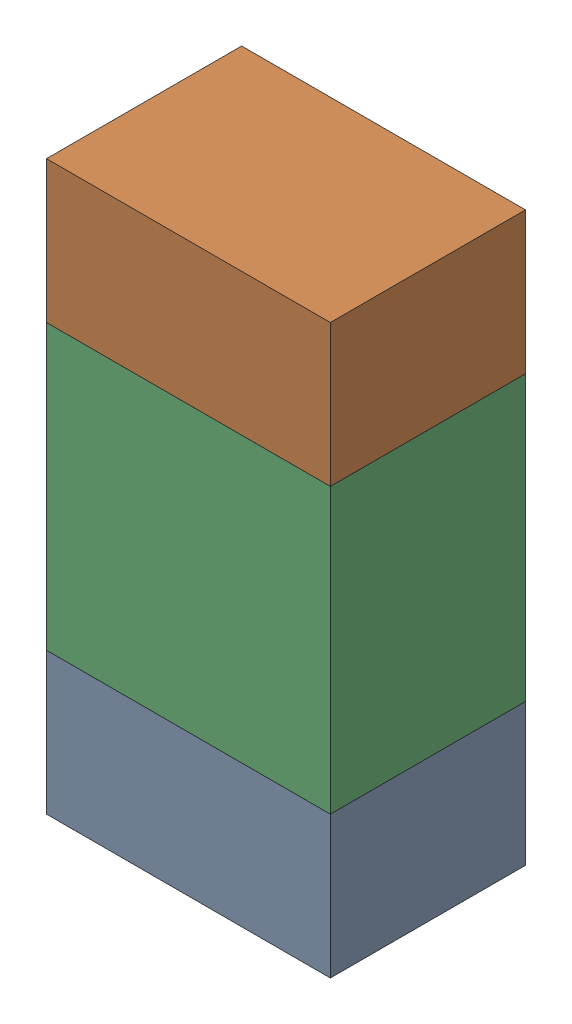
SolidWorks assembly R3, configuration ﾃﾞﾌｫﾙﾄ. Lengths in mm.
Overall size (0.8 1.6 0.55).
6 component instances, 2 part files, 0 mates.
Components (placement in the parent):
- 689261784-1: 689261784 [ﾃﾞﾌｫﾙﾄ] at (58.4999 40.4001 0) size (0.8 0.4 0.55)
  - Extruded_34-1: Extruded_34 [ﾃﾞﾌｫﾙﾄ] at origin size (0.8 0.4 0.55)
- 689261784-2: 689261784 [ﾃﾞﾌｫﾙﾄ] at (58.4999 41.6001 0) size (0.8 0.4 0.55)
  - Extruded_34-1: Extruded_34 [ﾃﾞﾌｫﾙﾄ] at origin size (0.8 0.4 0.55)
- 689261648-1: 689261648 [ﾃﾞﾌｫﾙﾄ] at (58.4999 41 0) size (0.8 0.8 0.55)
  - Extruded_33-1: Extruded_33 [ﾃﾞﾌｫﾙﾄ] at origin size (0.8 0.8 0.55)
